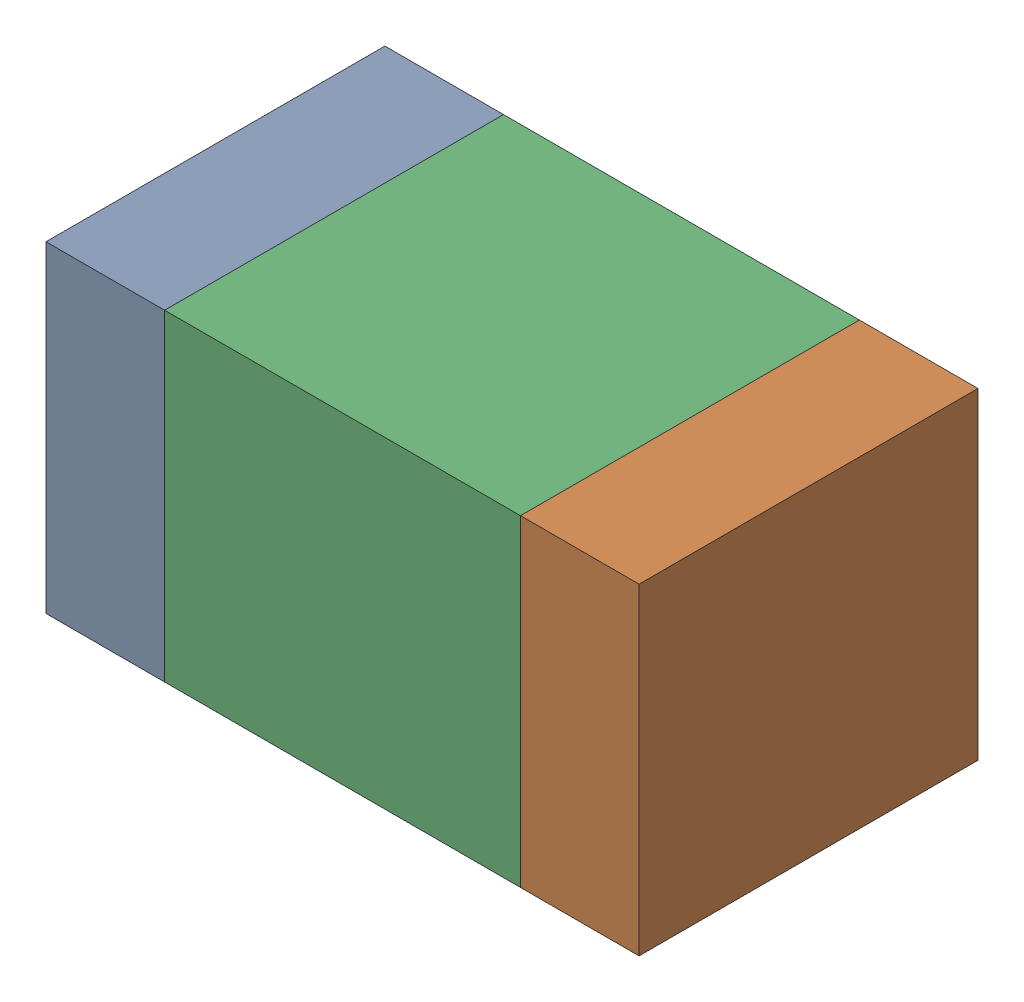
SolidWorks assembly C5-1, configuration Default. Lengths in mm.
Overall size (1.75 0.95 1).
6 component instances, 2 part files, 0 mates.
Components (placement in the parent):
- 959208936-1-1: 959208936-1 [Default] at (142.772 80.518 0) size (0.35 0.95 1)
  - Extruded-47-1: Extruded-47 [Default] at origin size (0.35 0.95 1)
- 959208936-1-2: 959208936-1 [Default] at (144.172 80.518 0) size (0.35 0.95 1)
  - Extruded-47-1: Extruded-47 [Default] at origin size (0.35 0.95 1)
- 959208800-1-1: 959208800-1 [Default] at (143.472 80.518 0) size (1.05 0.95 1)
  - Extruded-48-1: Extruded-48 [Default] at origin size (1.05 0.95 1)
